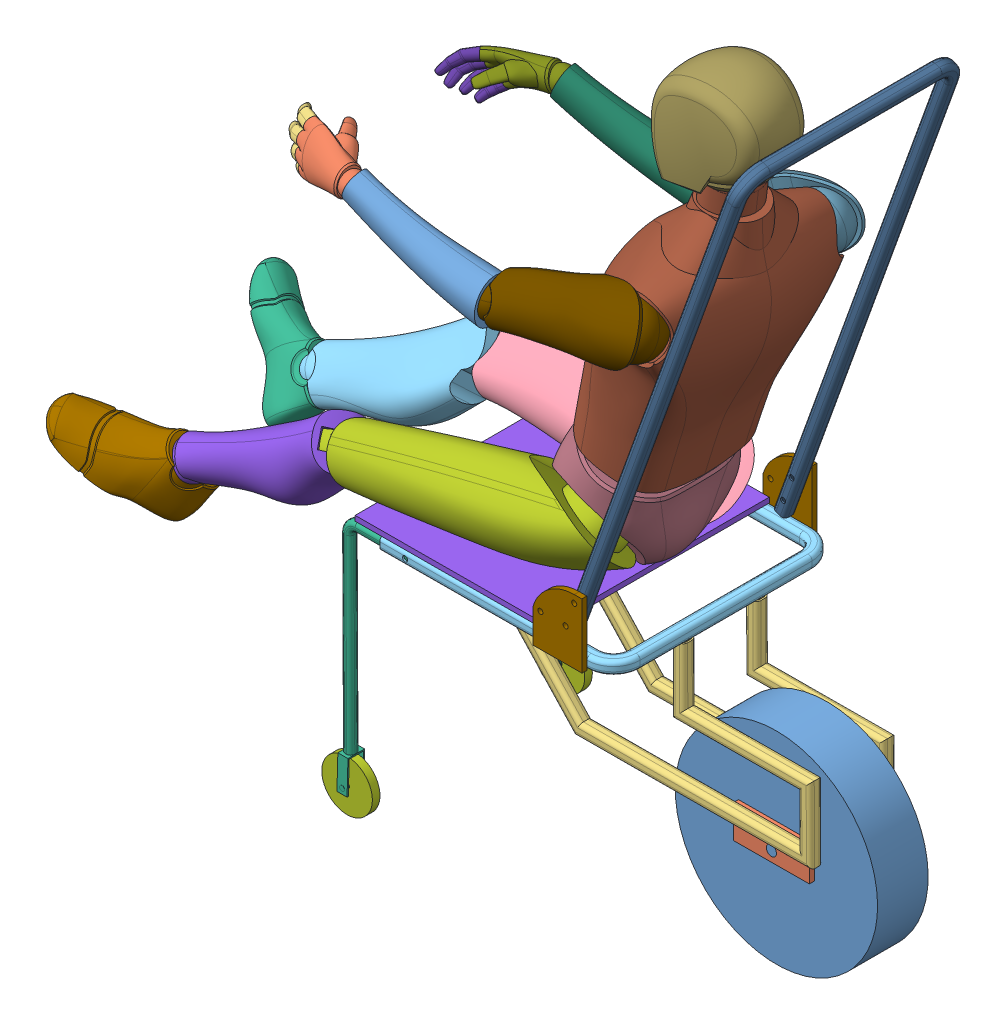
SolidWorks assembly AnalysisAssembly, configuration Default. Lengths in mm.
Overall size (1614.28 2927.71 2971.98).
35 component instances, 27 part files, 43 mates.
Components (placement in the parent):
- Wheel-2: Wheel [Default] at (-503.7515 200 2620.0822) x (0.679488 0.733687 0) z (0.733687 -0.679488 0) size (400 486.18 400)
- Wheel Platform-1: Wheel Platform [Default] at (-503.8066 212.4999 2720.0822) x (0.99999 0.004403 0) z (0.004403 -0.99999 0) size (150 10 65)
- Wheel Platform-2: Wheel Platform [Default] at (-503.8066 212.4999 2610.0822) x (0.99999 0.004403 0) z (0.004403 -0.99999 0) size (150 10 65)
- Lower Wheel Support-1: Lower Wheel Support [Default] at (-663.9283 239.7951 2597.5822) x (-0.99999 -0.004403 0) z (0.004403 -0.99999 0) size (711.33 35 323.58)
- Lower Wheel Support-2: Lower Wheel Support [Default] at (-663.9283 239.7951 2742.5822) x (-0.99999 -0.004403 0) z (0.004403 -0.99999 0) size (711.33 35 323.58)
- Circular Beam-1: Circular Beam [Default] at (-1105.0582 497.0268 2472.5822) x (0 0 1) z (0.788443 0.615108 0) size (395 20 20)
- Seat Platform-2: Seat Platform [Default] at (-1115.0798 500.3111 2460.7026) x (-0.99999 -0.004403 0) z (0 0 -1) size (462.5 62.5 445)
- Free Wheel Leg-1: Free Wheel Leg [Default] at (-836.7215 501.5368 2880.7026) x (-0.99999 -0.004403 0) z (0.004403 -0.99999 0) size (750 35.1 509.5)
- Free Wheel Leg-2: Free Wheel Leg [Default] at (-836.7215 501.5368 2460.7026) x (-0.99999 -0.004403 0) z (0.004403 -0.99999 0) size (750 35.1 509.5)
- Free Wheel-1: Free Wheel [Default] at (-1184.7366 50 2880.7026) x (-0.996508 -0.083495 0) z (-0.083495 0.996508 0) size (100 20.77 100)
- Free Wheel-2: Free Wheel [Default] at (-1184.7366 50 2460.7026) x (0.937503 -0.347977 0) z (-0.347977 -0.937503 0) size (100 20.77 100)
- Seat-1: Seat [Default] at (-976.7752 513.4202 2670.7026) x (0.99999 0.004403 0) z (0 0 1) size (380 10 439)
- Hinge-1: Hinge [Default] at (-705.0287 489.6165 2903.2026) x (-0.99999 -0.004403 0) z (0.004403 -0.99999 0) size (97.1 10 127)
- Hinge-2: Hinge [Default] at (-705.0287 489.6165 2448.2026) x (-0.99999 -0.004403 0) z (0.004403 -0.99999 0) size (97.1 10 127)
- Back Seat Platform-U Beam-1: Back Seat Platform-U Beam [Default] at (-747.551 526.2389 2460.7026) x (0 0 1) z (-0.337879 -0.94119 0) size (445 25 1012.5)
- Articulated_Dummy-1: Articulated_Dummy [Default] at (-1069.3633 -238.8581 2669.574) x (0.970478 -0.241174 0.002657) z (0.241173 0.970482 0.000499) size (1052.64 592.75 1430.49)
  - Torso-1: Torso [Default] at origin size (276.17 406.18 676.75)
  - Head-1: Head [Default] at (272.4966 0 13.9002) x (0.984808 0 0.173648) z (-0.173648 0 0.984808) size (223.51 154.11 248.99)
  - Pelvis-1: Pelvis [Default] at (-175.9416 -0.0047 21.1469) x (0.984808 0 -0.173648) z (0.173648 0 0.984808) size (220.9 294.19 237.82)
  - UpperArm_R-1: UpperArm_R [Default] at (-1164.6978 40.5521 782.9918) x (0.480784 0.0664 -0.874321) z (0.876833 -0.032757 0.479678) size (145.29 112.21 352.1)
  - LowerArm_R-1: LowerArm_R [Default] at (-1109.8206 -350.8514 1409.8475) x (-0.021504 -0.067308 -0.9975) z (0.939381 0.340144 -0.043203) size (97.1 110.82 304.02)
  - Hand_R-1: Hand_R [Default] at (-1026.554 -211.1082 756.2464) x (0.450032 0.495206 -0.74313) z (0.803724 0.138099 0.578754) size (143.51 200.25 239.15)
    - Hand_R-1: Hand_R [Default] at origin size (143.51 200.25 232.94)
    - Fingers_R-1: Fingers_R [Default] at origin size (103.08 62.21 73.67)
  - UpperArm_L-1: UpperArm_L [Default] at (-1154.4506 48.1192 789.555) x (0.383712 -0.421381 -0.821707) z (0.901636 -0.021319 0.431969) size (149.95 126.7 354.11)
  - LowerArm_L-1: LowerArm_L [Default] at (-1237.175 109.018 1373.4583) x (0.022959 0.087177 -0.995928) z (0.993849 -0.109941 0.013288) size (97.1 110.82 304.02)
  - Hand_L-1: Hand_L [Default] at (-1158.857 102.2382 896.6784) x (0.400695 -0.340847 -0.850451) z (0.891217 -0.070337 0.448091) size (143.54 200.25 239.15)
    - Hand_L-1: Hand_L [Default] at origin size (143.54 200.25 232.94)
    - Fingers_L-1: Fingers_L [Default] at origin size (103.08 62.28 73.68)
  - UpperLeg_R-1: UpperLeg_R [Default] at (-846.6749 137.4213 675.3146) x (0.202826 -0.686929 -0.697847) z (0.931594 -0.084173 0.35362) size (212.64 165.47 563.01)
  - LowerLeg_R-1: LowerLeg_R [Default] at (-769.3096 25.6211 503.3729) x (0.62768 -0.522628 -0.576956) z (0.723278 0.117422 0.6805) size (159.05 194.06 506.09)
  - Foot_R-1: Foot_R [Default] at (-744.6941 -0.9436 485.0971) x (0.785483 -0.333883 -0.521094) z (0.604301 0.232074 0.762209) size (250.01 160.41 191.51)
  - UpperLeg_L-1: UpperLeg_L [Default] at (-839.4632 -171.6805 657.1156) x (0.179608 0.724804 -0.665132) z (0.920043 0.115573 0.374385) size (212.64 165.47 563.01)
  - LowerLeg_L-1: LowerLeg_L [Default] at (-771.1336 -69.7092 493.1456) x (0.561883 0.655703 -0.504322) z (0.718877 -0.085418 0.689869) size (159.05 194.91 471.32)
  - Foot_L-1: Foot_L [Default] at (-730.9582 -37.7524 417.9636) x (0.868174 0.214838 -0.447345) z (0.453027 0.02488 0.89115) size (250.8 160.43 191.19)
Mates (geometry in assembly coordinates):
- Concentric1: concentric aligned: cylinder of Wheel-2 through (-503.7515 200 2610.0822) axis (0 0 1) radius 10; cylinder of Wheel Platform-1 through (-503.7515 200 2720.0822) axis (0 0 1) radius 10
- Coincident4: coincident anti-aligned: plane of Wheel-2 through (-503.7515 200 2720.0822) normal (0 0 1); plane of Wheel Platform-1 through (-503.8066 212.4999 2720.0822) normal (0 0 -1)
- Concentric2: concentric aligned: cylinder of Wheel-2 through (-503.7515 200 2610.0822) axis (0 0 1) radius 10; cylinder of Wheel Platform-2 through (-503.7515 200 2610.0822) axis (0 0 1) radius 10
- Coincident5: coincident anti-aligned: plane of Wheel-2 through (-503.7515 200 2620.0822) normal (0 0 -1); plane of Wheel Platform-2 through (-503.8066 212.4999 2620.0822) normal (0 0 1)
- Coincident6: coincident aligned: line of Wheel Platform-2 through (-428.9504 245.3298 2610.0822) axis (-0.99999 -0.004403 0); line of Lower Wheel Support-1 through (-418.4505 245.376 2610.0822) axis (-0.99999 -0.004403 0)
- Coincident7: coincident anti-aligned: plane of Wheel Platform-2 through (-503.8066 212.4999 2610.0822) normal (0 0 -1); plane of Lower Wheel Support-1 through (-660.5291 489.8125 2610.0822) normal (0 0 1)
- Coincident8: coincident aligned: line of Wheel Platform-1 through (-428.9504 245.3298 2730.0822) axis (-0.99999 -0.004403 0); line of Lower Wheel Support-2 through (-418.4505 245.376 2730.0822) axis (-0.99999 -0.004403 0)
- Coincident9: coincident anti-aligned: plane of Wheel Platform-1 through (-503.8066 212.4999 2730.0822) normal (0 0 1); plane of Lower Wheel Support-2 through (-660.5291 489.8125 2730.0822) normal (0 0 -1)
- Coincident10: coincident: line of assembly; point of Lower Wheel Support-2; line of Circular Beam-1 through (-1105.0582 497.0268 2472.5822) axis (0 0 1)
- Coincident11: coincident: line of assembly; point of Lower Wheel Support-1; line of Circular Beam-1 through (-1105.0582 497.0268 2472.5822) axis (0 0 1)
- Parallel3: parallel aligned: plane of Lower Wheel Support-1 through (-660.5291 489.8125 2585.0822) normal (0 0 -1); plane of Circular Beam-1 through (-1105.0582 497.0268 2472.5822) normal (0 0 -1)
- Width1: width anti-aligned: plane of Circular Beam-1 through (-1105.0582 497.0268 2867.5822) normal (0 0 1); plane of Circular Beam-1 through (-1105.0582 497.0268 2472.5822) normal (0 0 -1); plane of Wheel-2 through (-503.7515 200 2720.0822) normal (0 0 1); plane of Wheel-2 through (-503.7515 200 2620.0822) normal (0 0 -1)
- Coincident21: coincident: line of assembly; point of Wheel-2; line of Lower Wheel Support-1 through (-503.9298 240.4996 2620.0822) axis (0.004403 -0.99999 0)
- Coincident31: coincident aligned: line of Lower Wheel Support-1 through (-665.0291 489.7927 2597.5822) axis (0.004403 -0.99999 0); line of Seat Platform-2 through (-665.0841 502.2925 2597.5822) axis (0.004403 -0.99999 0)
- Parallel8: parallel anti-aligned: plane of Circular Beam-1 through (-1105.0582 497.0268 2867.5822) normal (0 0 1); plane of Seat Platform-2 through (-705.0639 497.6165 2868.2026) normal (0 0 -1)
- Coincident33: coincident anti-aligned: plane of Lower Wheel Support-1 through (-669.5291 489.7728 2602.0822) normal (-0.004403 0.99999 0); plane of Seat Platform-2 through (-1115.0247 487.8112 2456.2026) normal (0.004403 -0.99999 0)
- Parallel21: parallel anti-aligned: line of Lower Wheel Support-1 through (-503.9298 240.4996 2620.0822) axis (0.004403 -0.99999 0); line of Free Wheel Leg-2 through (-484.7434 53.0823 2460.7026) axis (-0.004403 0.99999 0)
- Coincident74: coincident anti-aligned: plane of Seat Platform-2 through (-1115.1216 509.811 2456.2026) normal (0.004403 -0.99999 0); plane of Free Wheel Leg-2 through (-836.7633 511.0367 2462.2026) normal (-0.004403 0.99999 0)
- Coincident73: coincident anti-aligned: plane of Seat Platform-2 through (-1115.06 495.8111 2451.2026) normal (0 0 1); plane of Free Wheel Leg-2 through (-836.7149 500.0368 2451.2026) normal (0 0 -1)
- Coincident77: coincident anti-aligned: plane of Seat Platform-2 through (-1115.1216 509.811 2456.2026) normal (0.004403 -0.99999 0); plane of Free Wheel Leg-1 through (-836.7633 511.0367 2882.2026) normal (-0.004403 0.99999 0)
- Coincident78: coincident anti-aligned: plane of Seat Platform-2 through (-705.0639 497.6165 2871.2026) normal (0 0 1); plane of Free Wheel Leg-1 through (-836.7149 500.0368 2871.2026) normal (0 0 -1)
- Distance4: distance = 700.024 mm: line of Free Wheel Leg-2 through (-1184.898 86.6528 2460.7026) axis (0.004403 -0.99999 0); line of Lower Wheel Support-1 through (-503.9298 240.4996 2620.0822) axis (0.004403 -0.99999 0)
- Coincident87: coincident aligned: plane of Free Wheel Leg-1 through (-1196.1299 479.954 2882.2026) normal (-0.99999 -0.004403 0); plane of Free Wheel Leg-2 through (-1196.1299 479.954 2462.2026) normal (-0.99999 -0.004403 0)
- Concentric3: concentric anti-aligned: cylinder of Free Wheel Leg-1 through (-1184.7366 50 2898.2026) axis (0 0 -1) radius 5; cylinder of Free Wheel-1 through (-1184.7366 50 2873.2026) axis (0 0 1) radius 5
- Width5: width anti-aligned: plane of Free Wheel-1 through (-1184.7366 50 2888.2026) normal (0 0 1); plane of Free Wheel-1 through (-1184.7366 50 2873.2026) normal (0 0 -1); plane of Free Wheel Leg-1 through (-1184.7366 50 2863.2026) normal (0 0 -1); plane of Free Wheel Leg-1 through (-1184.7366 50 2898.2026) normal (0 0 1)
- Concentric4: concentric anti-aligned: cylinder of Free Wheel Leg-2 through (-1184.7366 50 2478.2026) axis (0 0 -1) radius 5; cylinder of Free Wheel-2 through (-1184.7366 50 2453.2026) axis (0 0 1) radius 5
- Width6: width anti-aligned: plane of Free Wheel-2 through (-1184.7366 50 2468.2026) normal (0 0 1); plane of Free Wheel-2 through (-1184.7366 50 2453.2026) normal (0 0 -1); plane of Free Wheel Leg-2 through (-1184.7366 50 2443.2026) normal (0 0 -1); plane of Free Wheel Leg-2 through (-1184.7366 50 2478.2026) normal (0 0 1)
- Coincident90: coincident anti-aligned: plane of Seat Platform-2 through (-1115.1348 512.811 2456.2026) normal (-0.004403 0.99999 0); plane of Seat-1 through (-976.7752 513.4202 2670.7026) normal (0.004403 -0.99999 0)
- Coincident91: coincident: line of Free Wheel Leg-1 through (-1166.7601 509.5836 2882.2026) axis (0 0 -1); plane of Seat-1 through (-1166.8174 522.5835 2890.2026) normal (-0.99999 -0.004403 0)
- Width7: width anti-aligned: plane of Seat-1 through (-1166.8174 522.5835 2890.2026) normal (0 0 1); plane of Seat-1 through (-1166.8174 522.5835 2451.2026) normal (0 0 -1); plane of Seat Platform-2 through (-1115.06 495.8111 2448.2026) normal (0 0 -1); plane of Seat Platform-2 through (-705.0639 497.6165 2893.2026) normal (0 0 1)
- Coincident92: coincident anti-aligned: plane of Seat Platform-2 through (-705.0639 497.6165 2893.2026) normal (0 0 1); plane of Hinge-1 through (-720.2119 531.1919 2893.2026) normal (0 0 -1)
- Coincident93: coincident aligned: plane of Seat Platform-2 through (-1115.0247 487.8112 2456.2026) normal (0.004403 -0.99999 0); plane of Hinge-1 through (-705.0287 489.6165 2893.2026) normal (0.004403 -0.99999 0)
- Coincident94: coincident aligned: line of Seat Platform-2 through (-705.1036 506.6164 2893.2026) axis (0.004403 -0.99999 0); line of Hinge-1 through (-705.5879 616.6153 2893.2026) axis (0.004403 -0.99999 0)
- Coincident95: coincident anti-aligned: plane of Seat Platform-2 through (-1115.06 495.8111 2448.2026) normal (0 0 -1); plane of Hinge-2 through (-720.2119 531.1919 2448.2026) normal (0 0 1)
- Coincident96: coincident aligned: plane of Seat Platform-2 through (-1115.0247 487.8112 2456.2026) normal (0.004403 -0.99999 0); plane of Hinge-2 through (-705.0287 489.6165 2438.2026) normal (0.004403 -0.99999 0)
- Coincident97: coincident aligned: line of Seat Platform-2 through (-705.1036 506.6164 2448.2026) axis (0.004403 -0.99999 0); line of Hinge-2 through (-705.5879 616.6153 2448.2026) axis (0.004403 -0.99999 0)
- Concentric5: concentric anti-aligned: cylinder of Hinge-2 through (-737.4146 554.4746 2448.2026) axis (0 0 -1) radius 5; cylinder of Back Seat Platform-U Beam-1 through (-737.4146 554.4746 2448.2026) axis (0 0 1) radius 5
- Concentric6: concentric anti-aligned: cylinder of Hinge-2 through (-720.5207 601.534 2448.2026) axis (0 0 -1) radius 5; cylinder of Back Seat Platform-U Beam-1 through (-720.5207 601.534 2448.2026) axis (0 0 1) radius 5
- Coincident98: coincident anti-aligned: plane of Hinge-2 through (-720.2119 531.1919 2448.2026) normal (0 0 1); plane of Back Seat Platform-U Beam-1 through (-743.3156 524.7184 2448.2026) normal (0 0 -1)
- Coincident108: coincident anti-aligned: plane of Articulated_Dummy-1 through (-578.7456 996.4599 2670.7026) normal (0.94119 -0.337879 0)
- Coincident113: coincident anti-aligned: plane of Articulated_Dummy-1 through (-1069.3633 -238.8581 2670.7026) normal (0 0 1)
- Tangent8: tangent anti-aligned: plane of Seat-1 through (-976.8192 523.4201 2670.7026) normal (-0.004403 0.99999 0); face of Articulated_Dummy-1/Pelvis-1
- Concentric7: concentric aligned: cylinder of Wheel Platform-1 through (-503.7515 200 2720.0822) axis (0 0 1) radius 10; cylinder of Wheel Platform-2 through (-503.7515 200 2610.0822) axis (0 0 1) radius 10
